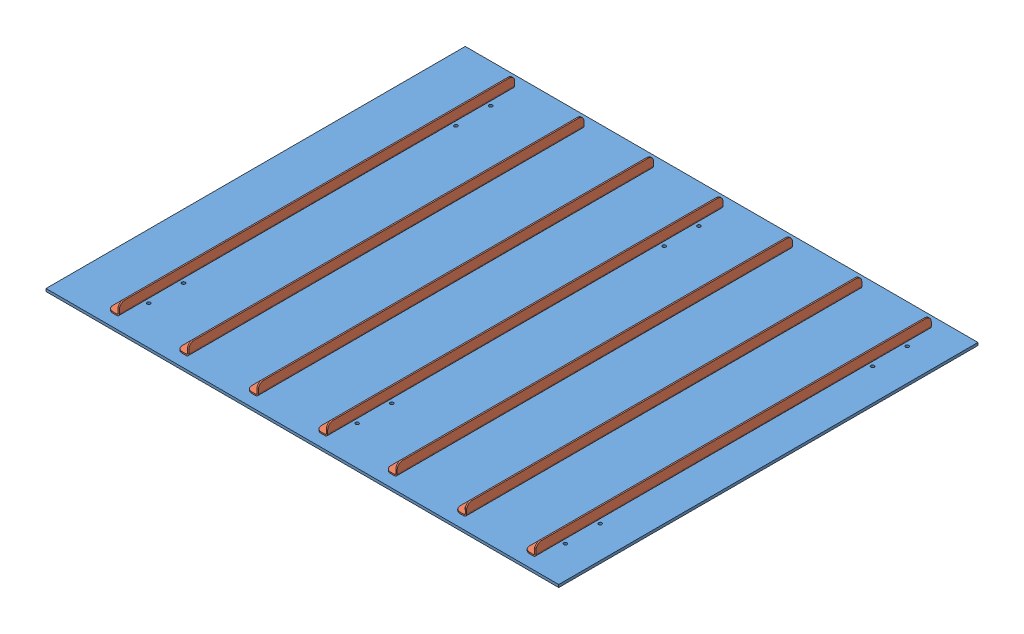
SolidWorks assembly GE-22004, configuration Default. Lengths in mm.
Overall size (1219.2 36.53 996.95).
36 component instances, 3 part files, 11 mates.
Components (placement in the parent):
- GE-22005-1: GE-22005 [Default] at (201.9906 725.0038 1009.0986) size (1219.2 6.35 996.95)
- GE-22006-1: GE-22006 [Default] at (714.7531 734.5288 1009.0986) x (0 0 1) z (-1 0 0) size (939.8 28.57 28.57)
- rivet_.1875_.251-.375-1: rivet_.1875_.251-.375 [Default] at (716.3406 725.0038 1466.2986) x (1 0 0) z (0 -1 0) size (10.01 10.01 16.21)
- rivet_.1875_.251-.375-2: rivet_.1875_.251-.375 [Default] at (716.3406 725.0038 1161.4986) x (0.982082 0 -0.188455) z (0 -1 0) size (10.01 10.01 16.21)
- rivet_.1875_.251-.375-3: rivet_.1875_.251-.375 [Default] at (716.3406 725.0038 856.6986) x (0.918365 0 -0.395734) z (0 -1 0) size (10.01 10.01 16.21)
- rivet_.1875_.251-.375-4: rivet_.1875_.251-.375 [Default] at (716.3406 725.0038 551.8986) x (0.8 0 -0.6) z (0 -1 0) size (10.01 10.01 16.21)
- rivet_.1875_.251-.375-6: rivet_.1875_.251-.375 [Default] at (551.2406 725.0038 551.8986) x (0.8 0 -0.6) z (0 -1 0) size (10.01 10.01 16.21)
- rivet_.1875_.251-.375-7: rivet_.1875_.251-.375 [Default] at (386.1406 725.0038 551.8986) x (0.8 0 -0.6) z (0 -1 0) size (10.01 10.01 16.21)
- rivet_.1875_.251-.375-8: rivet_.1875_.251-.375 [Default] at (221.0406 725.0038 551.8986) x (0.8 0 -0.6) z (0 -1 0) size (10.01 10.01 16.21)
- rivet_.1875_.251-.375-9: rivet_.1875_.251-.375 [Default] at (55.9406 725.0038 551.8986) x (0.8 0 -0.6) z (0 -1 0) size (10.01 10.01 16.21)
- rivet_.1875_.251-.375-10: rivet_.1875_.251-.375 [Default] at (-109.1594 725.0038 551.8986) x (0.8 0 -0.6) z (0 -1 0) size (10.01 10.01 16.21)
- rivet_.1875_.251-.375-11: rivet_.1875_.251-.375 [Default] at (-274.2594 725.0038 551.8986) x (0.8 0 -0.6) z (0 -1 0) size (10.01 10.01 16.21)
- rivet_.1875_.251-.375-12: rivet_.1875_.251-.375 [Default] at (551.2406 725.0038 856.6986) x (0.918365 0 -0.395734) z (0 -1 0) size (10.01 10.01 16.21)
- rivet_.1875_.251-.375-13: rivet_.1875_.251-.375 [Default] at (386.1406 725.0038 856.6986) x (0.918365 0 -0.395734) z (0 -1 0) size (10.01 10.01 16.21)
- rivet_.1875_.251-.375-14: rivet_.1875_.251-.375 [Default] at (221.0406 725.0038 856.6986) x (0.918365 0 -0.395734) z (0 -1 0) size (10.01 10.01 16.21)
- rivet_.1875_.251-.375-15: rivet_.1875_.251-.375 [Default] at (55.9406 725.0038 856.6986) x (0.918365 0 -0.395734) z (0 -1 0) size (10.01 10.01 16.21)
- rivet_.1875_.251-.375-16: rivet_.1875_.251-.375 [Default] at (-109.1594 725.0038 856.6986) x (0.918365 0 -0.395734) z (0 -1 0) size (10.01 10.01 16.21)
- rivet_.1875_.251-.375-17: rivet_.1875_.251-.375 [Default] at (-274.2594 725.0038 856.6986) x (0.918365 0 -0.395734) z (0 -1 0) size (10.01 10.01 16.21)
- rivet_.1875_.251-.375-18: rivet_.1875_.251-.375 [Default] at (551.2406 725.0038 1161.4986) x (0.982082 0 -0.188455) z (0 -1 0) size (10.01 10.01 16.21)
- rivet_.1875_.251-.375-19: rivet_.1875_.251-.375 [Default] at (386.1406 725.0038 1161.4986) x (0.982082 0 -0.188455) z (0 -1 0) size (10.01 10.01 16.21)
- rivet_.1875_.251-.375-20: rivet_.1875_.251-.375 [Default] at (221.0406 725.0038 1161.4986) x (0.982082 0 -0.188455) z (0 -1 0) size (10.01 10.01 16.21)
- rivet_.1875_.251-.375-21: rivet_.1875_.251-.375 [Default] at (55.9406 725.0038 1161.4986) x (0.982082 0 -0.188455) z (0 -1 0) size (10.01 10.01 16.21)
- rivet_.1875_.251-.375-22: rivet_.1875_.251-.375 [Default] at (-109.1594 725.0038 1161.4986) x (0.982082 0 -0.188455) z (0 -1 0) size (10.01 10.01 16.21)
- rivet_.1875_.251-.375-23: rivet_.1875_.251-.375 [Default] at (-274.2594 725.0038 1161.4986) x (0.982082 0 -0.188455) z (0 -1 0) size (10.01 10.01 16.21)
- rivet_.1875_.251-.375-24: rivet_.1875_.251-.375 [Default] at (551.2406 725.0038 1466.2986) x (1 0 0) z (0 -1 0) size (10.01 10.01 16.21)
- rivet_.1875_.251-.375-25: rivet_.1875_.251-.375 [Default] at (386.1406 725.0038 1466.2986) x (1 0 0) z (0 -1 0) size (10.01 10.01 16.21)
- rivet_.1875_.251-.375-26: rivet_.1875_.251-.375 [Default] at (221.0406 725.0038 1466.2986) x (1 0 0) z (0 -1 0) size (10.01 10.01 16.21)
- rivet_.1875_.251-.375-27: rivet_.1875_.251-.375 [Default] at (55.9406 725.0038 1466.2986) x (1 0 0) z (0 -1 0) size (10.01 10.01 16.21)
- rivet_.1875_.251-.375-28: rivet_.1875_.251-.375 [Default] at (-109.1594 725.0038 1466.2986) x (1 0 0) z (0 -1 0) size (10.01 10.01 16.21)
- rivet_.1875_.251-.375-29: rivet_.1875_.251-.375 [Default] at (-274.2594 725.0038 1466.2986) x (1 0 0) z (0 -1 0) size (10.01 10.01 16.21)
- GE-22006-2: GE-22006 [Default] at (549.6531 734.5288 1009.0986) x (0 0 1) z (-1 0 0) size (939.8 28.57 28.57)
- GE-22006-3: GE-22006 [Default] at (384.5531 734.5288 1009.0986) x (0 0 1) z (-1 0 0) size (939.8 28.57 28.57)
- GE-22006-4: GE-22006 [Default] at (219.4531 734.5288 1009.0986) x (0 0 1) z (-1 0 0) size (939.8 28.57 28.57)
- GE-22006-5: GE-22006 [Default] at (54.3531 734.5288 1009.0986) x (0 0 1) z (-1 0 0) size (939.8 28.57 28.57)
- GE-22006-6: GE-22006 [Default] at (-110.7469 734.5288 1009.0986) x (0 0 1) z (-1 0 0) size (939.8 28.57 28.57)
- GE-22006-7: GE-22006 [Default] at (-275.8469 734.5288 1009.0986) x (0 0 1) z (-1 0 0) size (939.8 28.57 28.57)
Mates (geometry in assembly coordinates):
- Coincident1: coincident anti-aligned: plane of GE-22005-1 through (201.9906 731.3538 1009.0986) normal (0 1 0); plane of GE-22006-1 through (714.7531 731.3538 1009.0986) normal (0 -1 0)
- Concentric1: concentric aligned: cylinder of GE-22005-1 through (716.3406 731.3538 1466.2986) axis (0 1 0) radius 2.5798; cylinder of GE-22006-1 through (716.3406 734.5288 1466.2986) axis (0 1 0) radius 2.4257
- Concentric2: concentric aligned: cylinder of GE-22005-1 through (716.3406 731.3538 551.8986) axis (0 1 0) radius 2.5798; cylinder of GE-22006-1 through (716.3406 734.5288 551.8986) axis (0 1 0) radius 2.4257
- Concentric3: concentric anti-aligned: cylinder of GE-22006-1 through (716.3406 734.5288 1466.2986) axis (0 1 0) radius 2.4257; cylinder of rivet_.1875_.251-.375-1 through (716.3406 739.6088 1466.2986) axis (0 -1 0) radius 2.3813
- Distance1: distance = 6.35 mm anti-aligned: plane of GE-22006-1 through (714.7531 731.3538 1009.0986) normal (0 -1 0); plane of rivet_.1875_.251-.375-1 through (716.3406 725.0038 1466.2986) normal (0 1 0)
- Distance2: distance = 6.35 mm anti-aligned: plane of GE-22006-1 through (714.7531 731.3538 1009.0986) normal (0 -1 0); plane of rivet_.1875_.251-.375-2 through (716.3406 725.0038 1161.4986) normal (0 1 0)
- Concentric4: concentric anti-aligned: cylinder of GE-22006-1 through (716.3406 734.5288 1161.4986) axis (0 1 0) radius 2.4257; cylinder of rivet_.1875_.251-.375-2 through (716.3406 739.6088 1161.4986) axis (0 -1 0) radius 2.3813
- Distance3: distance = 6.35 mm anti-aligned: plane of GE-22006-1 through (714.7531 731.3538 1009.0986) normal (0 -1 0); plane of rivet_.1875_.251-.375-3 through (716.3406 725.0038 856.6986) normal (0 1 0)
- Concentric5: concentric anti-aligned: cylinder of GE-22006-1 through (716.3406 734.5288 856.6986) axis (0 1 0) radius 2.4257; cylinder of rivet_.1875_.251-.375-3 through (716.3406 739.6088 856.6986) axis (0 -1 0) radius 2.3813
- Distance4: distance = 6.35 mm anti-aligned: plane of GE-22006-1 through (714.7531 731.3538 1009.0986) normal (0 -1 0); plane of rivet_.1875_.251-.375-4 through (716.3406 725.0038 551.8986) normal (0 1 0)
- Concentric6: concentric anti-aligned: cylinder of GE-22006-1 through (716.3406 734.5288 551.8986) axis (0 1 0) radius 2.4257; cylinder of rivet_.1875_.251-.375-4 through (716.3406 739.6088 551.8986) axis (0 -1 0) radius 2.3813
